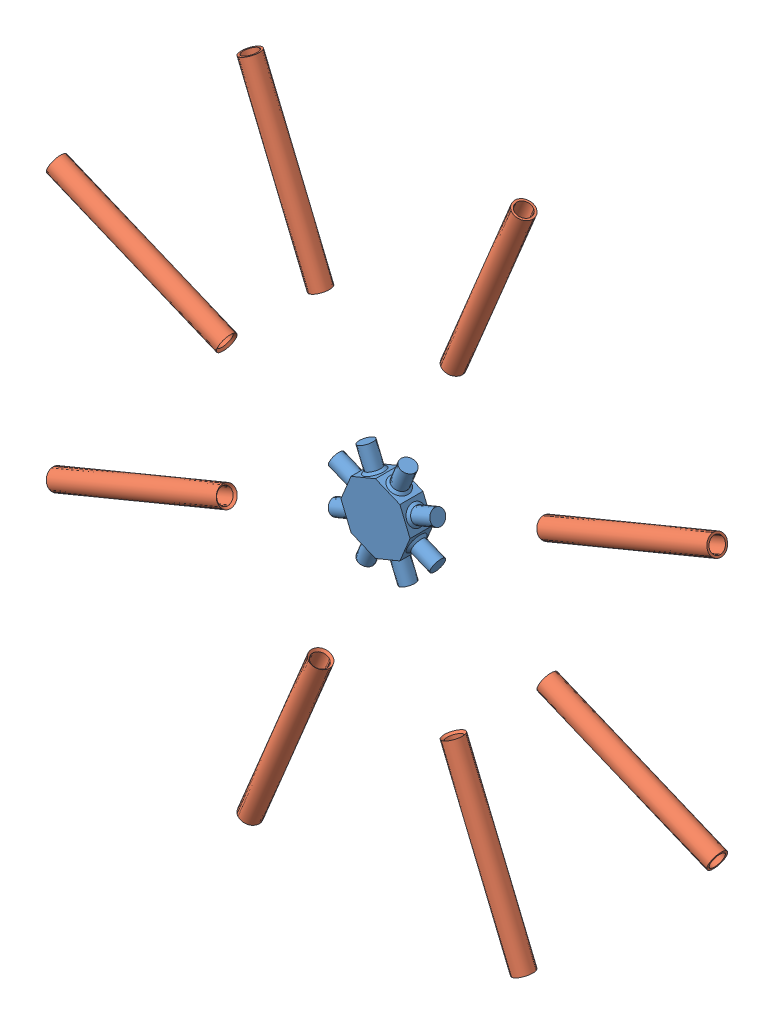
SolidWorks assembly Assem1, configuration Default. Lengths in mm.
Overall size (739.94 739.94 29.95).
9 component instances, 2 part files, 2 mates.
Components (placement in the parent):
- Hub 060815-1: Hub 060815 [Default] at (7.0285 57.2336 113.4461) size (118.29 118.29 25.4)
- Tube 060815-1: Tube 060815 [Default] at (-169.477 130.3446 113.4461) x (-0.92388 0.382683 0) z (0.318118 0.768006 -0.555849) size (202.95 21.59 21.59)
- Tube 060815-2: Tube 060815 [Default] at (-66.0825 233.7392 113.4461) x (-0.382683 0.92388 0) z (0.768006 0.318118 -0.555849) size (202.95 21.59 21.59)
- Tube 060815-3: Tube 060815 [Default] at (80.1395 233.7392 113.4461) x (0.382683 0.92388 0) z (0.768006 -0.318118 -0.555849) size (202.95 21.59 21.59)
- Tube 060815-4: Tube 060815 [Default] at (183.5341 130.3446 113.4461) x (0.92388 0.382683 0) z (0.318118 -0.768006 -0.555849) size (202.95 21.59 21.59)
- Tube 060815-5: Tube 060815 [Default] at (183.5341 -15.8774 113.4461) x (0.92388 -0.382683 0) z (-0.318118 -0.768006 -0.555849) size (202.95 21.59 21.59)
- Tube 060815-6: Tube 060815 [Default] at (80.1395 -119.272 113.4461) x (0.382683 -0.92388 0) z (-0.768006 -0.318118 -0.555849) size (202.95 21.59 21.59)
- Tube 060815-7: Tube 060815 [Default] at (-66.0825 -119.272 113.4461) x (-0.382683 -0.92388 0) z (-0.768006 0.318118 -0.555849) size (202.95 21.59 21.59)
- Tube 060815-8: Tube 060815 [Default] at (-169.477 -15.8774 113.4461) x (-0.92388 -0.382683 0) z (-0.318118 0.768006 -0.555849) size (202.95 21.59 21.59)
Mates (geometry in assembly coordinates):
- Concentric1: concentric aligned: cone of Hub 060815-1 through (-27.8385 71.676 113.4461) axis (-0.92388 0.382683 0); cone of Tube 060815-1 through (-169.477 130.3446 113.4461) axis (-0.92388 0.382683 0)
- Coincident1: coincident aligned: cone of Hub 060815-1 through (-27.8385 71.676 113.4461) axis (-0.92388 0.382683 0); cone of Tube 060815-1 through (-168.4686 129.9269 113.4461) axis (-0.92388 0.382683 0)
